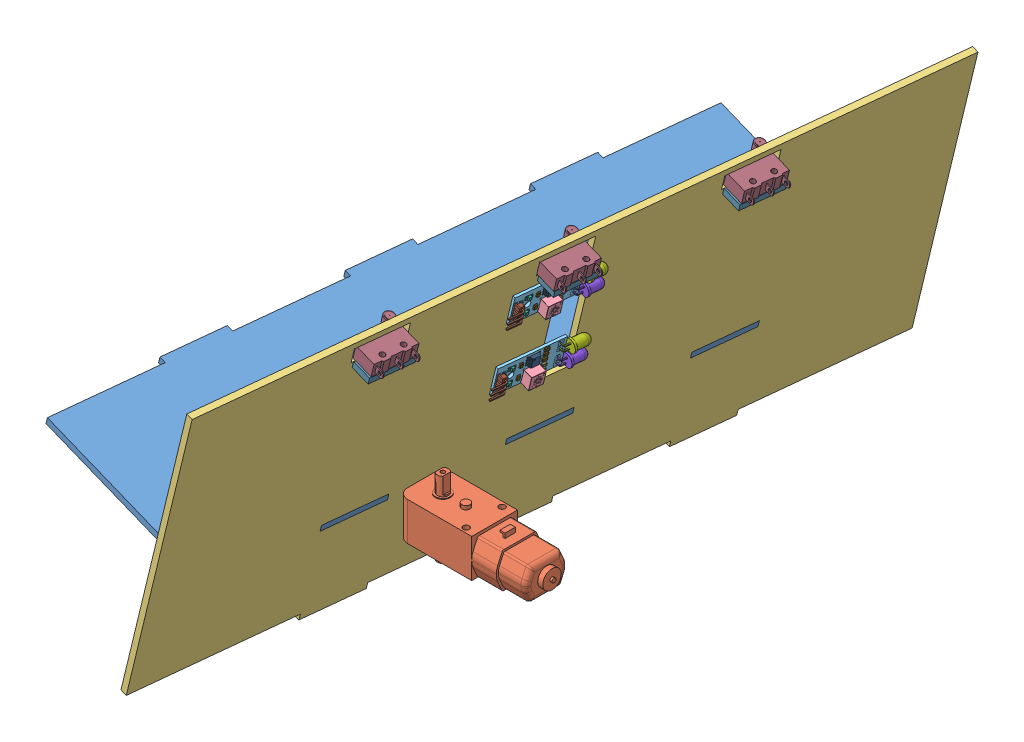
SolidWorks assembly Ensamblaje1, configuration Predeterminado. Lengths in mm.
Overall size (238.35 140.66 351.54).
45 component instances, 23 part files, 27 mates.
Components (placement in the parent):
- base-1: base [Predeterminado] at (-119.379 -243.9232 35.3077) x (0.963008 -0.251135 0.097703) z (-0.099836 0.004266 0.994995) size (91 3 300)
- Motor-1: Motor [Predeterminado] at (5.9789 -196.2669 168.1272) size (70.2 36.87 22.3)
- ParedDerecha-1: ParedDerecha [Predeterminado] at (-71.4428 -227.4941 40.047) x (0.099836 -0.004266 -0.994995) z (0.963008 -0.251135 0.097703) size (350 143 3)
- Sensor_IR.stp-1: Sensor_IR.stp [Predeterminado] at (-66.8981 -216.5746 54.0241) x (0.099836 -0.004266 -0.994995) z (0.963008 -0.251135 0.097703) size (45.22 14 7.87)
  - 3362P-1-102LF.stp-1: 3362P-1-102LF.stp [Predeterminado] at (0.5 -3.2 1.53) x (1 0 0) z (0 -1 0) size (6.6 7.58 6.6)
  - IR_Sensor_FC-51_1.stp-1: IR_Sensor_FC-51_1.stp [Predeterminado] at origin size (31 14 1.25)
  - KPTR-3216CGCK.stp-1: KPTR-3216CGCK.stp [Predeterminado] at (-8.7 3.8 1.45) x (1 0 0) z (0 0 -1) size (3.2 1.6 1.05)
  - KPTR-3216CGCK.stp-2: KPTR-3216CGCK.stp [Predeterminado] at (-8.7 -3.8 1.45) x (1 0 0) z (0 0 -1) size (3.2 1.6 1.05)
  - LED 5mm.stp-1: LED 5mm.stp [Predeterminado] at (15.74 3.64 3) x (0 1 0) z (1 0 0) size (5.5 6.7 11.78)
  - LED 5mm_foto.stp-1: LED 5mm_foto.stp [Predeterminado] at (15.74 -3.64 3) x (0 1 0) z (1 0 0) size (5.5 6.7 11.78)
  - RESC-0805.stp-1: RESC-0805.stp [Predeterminado] at (-4.525 -3.15 1.2) x (0 -1 0) z (0 0 1) size (2.1 1.35 0.6)
  - RESC-0805.stp-2: RESC-0805.stp [Predeterminado] at (-4.525 3.25 1.2) x (0 1 0) z (0 0 1) size (2.1 1.35 0.6)
  - SOIC8-150-50.stp-1: SOIC8-150-50.stp [Predeterminado] at (0.55 3.85 1.2) x (1 0 0) z (0 -1 0) size (6 1.91 4.9)
  - 1 Pin 2.54 mm Right Angle Single Row Pin Header Male 90 degrees Needle Connector.stp-1: 1 Pin 2.54 mm Right Angle Single Row Pin Header Male 90 degrees Needle Connector.stp [Predeterminado] at (-13.5 2.54 -1.76) x (-1 0 0) z (0 0 1) size (8.45 2.54 7.3)
  - 1 Pin 2.54 mm Right Angle Single Row Pin Header Male 90 degrees Needle Connector.stp-2: 1 Pin 2.54 mm Right Angle Single Row Pin Header Male 90 degrees Needle Connector.stp [Predeterminado] at (-13.5 0 -1.76) x (-1 0 0) z (0 0 1) size (8.45 2.54 7.3)
  - 1 Pin 2.54 mm Right Angle Single Row Pin Header Male 90 degrees Needle Connector.stp-3: 1 Pin 2.54 mm Right Angle Single Row Pin Header Male 90 degrees Needle Connector.stp [Predeterminado] at (-13.5 -2.54 -1.76) x (-1 0 0) z (0 0 1) size (8.45 2.54 7.3)
  - RESC-0805.stp-3: RESC-0805.stp [Predeterminado] at (6.45 5.625 1.2) size (2.1 1.35 0.6)
  - RESC-0805.stp-4: RESC-0805.stp [Predeterminado] at (6.45 3.085 1.2) size (2.1 1.35 0.6)
  - RESC-0805.stp-5: RESC-0805.stp [Predeterminado] at (6.45 0.545 1.2) size (2.1 1.35 0.6)
  - CAPC-0805-T0.95-BN.stp-1: CAPC-0805-T0.95-BN.stp [Predeterminado] at (6.45 -1.995 1.2) size (2.1 1.35 0.95)
  - CAPC-0805-T0.95-BN.stp-2: CAPC-0805-T0.95-BN.stp [Predeterminado] at (6.45 -4.535 1.2) size (2.1 1.35 0.95)
- Fin_Carrera.step-1: Fin_Carrera.step [Predeterminado] at (-50.8661 -171.0598 50.7642) x (-0.099836 0.004266 0.994995) z (-0.250295 -0.967943 -0.020964) size (22.47 22.8 6.34)
- Sensor_IR.stp-2: Sensor_IR.stp [Predeterminado] at (-57.8874 -181.7286 54.7788) x (0.099836 -0.004266 -0.994995) z (0.963008 -0.251135 0.097703) size (45.22 14 7.87)
  - 3362P-1-102LF.stp-1: 3362P-1-102LF.stp [Predeterminado] at (0.5 -3.2 1.53) x (1 0 0) z (0 -1 0) size (6.6 7.58 6.6)
  - IR_Sensor_FC-51_1.stp-1: IR_Sensor_FC-51_1.stp [Predeterminado] at origin size (31 14 1.25)
  - KPTR-3216CGCK.stp-1: KPTR-3216CGCK.stp [Predeterminado] at (-8.7 3.8 1.45) x (1 0 0) z (0 0 -1) size (3.2 1.6 1.05)
  - KPTR-3216CGCK.stp-2: KPTR-3216CGCK.stp [Predeterminado] at (-8.7 -3.8 1.45) x (1 0 0) z (0 0 -1) size (3.2 1.6 1.05)
  - LED 5mm.stp-1: LED 5mm.stp [Predeterminado] at (15.74 3.64 3) x (0 1 0) z (1 0 0) size (5.5 6.7 11.78)
  - LED 5mm_foto.stp-1: LED 5mm_foto.stp [Predeterminado] at (15.74 -3.64 3) x (0 1 0) z (1 0 0) size (5.5 6.7 11.78)
  - RESC-0805.stp-1: RESC-0805.stp [Predeterminado] at (-4.525 -3.15 1.2) x (0 -1 0) z (0 0 1) size (2.1 1.35 0.6)
  - RESC-0805.stp-2: RESC-0805.stp [Predeterminado] at (-4.525 3.25 1.2) x (0 1 0) z (0 0 1) size (2.1 1.35 0.6)
  - SOIC8-150-50.stp-1: SOIC8-150-50.stp [Predeterminado] at (0.55 3.85 1.2) x (1 0 0) z (0 -1 0) size (6 1.91 4.9)
  - 1 Pin 2.54 mm Right Angle Single Row Pin Header Male 90 degrees Needle Connector.stp-1: 1 Pin 2.54 mm Right Angle Single Row Pin Header Male 90 degrees Needle Connector.stp [Predeterminado] at (-13.5 2.54 -1.76) x (-1 0 0) z (0 0 1) size (8.45 2.54 7.3)
  - 1 Pin 2.54 mm Right Angle Single Row Pin Header Male 90 degrees Needle Connector.stp-2: 1 Pin 2.54 mm Right Angle Single Row Pin Header Male 90 degrees Needle Connector.stp [Predeterminado] at (-13.5 0 -1.76) x (-1 0 0) z (0 0 1) size (8.45 2.54 7.3)
  - 1 Pin 2.54 mm Right Angle Single Row Pin Header Male 90 degrees Needle Connector.stp-3: 1 Pin 2.54 mm Right Angle Single Row Pin Header Male 90 degrees Needle Connector.stp [Predeterminado] at (-13.5 -2.54 -1.76) x (-1 0 0) z (0 0 1) size (8.45 2.54 7.3)
  - RESC-0805.stp-3: RESC-0805.stp [Predeterminado] at (6.45 5.625 1.2) size (2.1 1.35 0.6)
  - RESC-0805.stp-4: RESC-0805.stp [Predeterminado] at (6.45 3.085 1.2) size (2.1 1.35 0.6)
  - RESC-0805.stp-5: RESC-0805.stp [Predeterminado] at (6.45 0.545 1.2) size (2.1 1.35 0.6)
  - CAPC-0805-T0.95-BN.stp-1: CAPC-0805-T0.95-BN.stp [Predeterminado] at (6.45 -1.995 1.2) size (2.1 1.35 0.95)
  - CAPC-0805-T0.95-BN.stp-2: CAPC-0805-T0.95-BN.stp [Predeterminado] at (6.45 -4.535 1.2) size (2.1 1.35 0.95)
- soporteFinCarrera-1: soporteFinCarrera [Predeterminado] at (-58.4739 -172.2659 54.1769) x (0.099836 -0.004266 -0.994995) z (0.963008 -0.251135 0.097703) size (21 3 12)
- soporteFinCarrera-2: soporteFinCarrera [Predeterminado] at (-48.4882 -169.7567 -37.7972) x (-0.099836 0.004266 0.994995) z (0.963008 -0.251135 0.097703) size (21 3 12)
- soporteFinCarrera-3: soporteFinCarrera [Predeterminado] at (-64.9611 -169.0527 126.3769) x (-0.099836 0.004266 0.994995) z (0.963008 -0.251135 0.097703) size (21 3 12)
- Fin_Carrera.step-2: Fin_Carrera.step [Predeterminado] at (-42.5099 -171.4169 -32.5169) x (-0.099836 0.004266 0.994995) z (-0.250295 -0.967943 -0.020964) size (22.47 22.8 6.34)
- Fin_Carrera.step-3: Fin_Carrera.step [Predeterminado] at (-58.9828 -170.713 131.6573) x (-0.099836 0.004266 0.994995) z (-0.250295 -0.967943 -0.020964) size (22.47 22.8 6.34)
Mates (geometry in assembly coordinates):
- Coincidente1: coincident anti-aligned: plane of base-1 through (-119.379 -243.9232 35.3077) normal (-0.250295 -0.967943 -0.020964); plane of ParedDerecha-1 through (-75.5621 -255.3499 39.7531) normal (0.250295 0.967943 0.020964)
- Coincidente2: coincident anti-aligned: plane of base-1 through (-84.4391 -251.4046 106.6851) normal (0.099836 -0.004266 -0.994995); plane of ParedDerecha-1 through (-75.2927 -227.9595 107.5023) normal (-0.099836 0.004266 0.994995)
- Coincidente3: coincident aligned: plane of base-1 through (-84.5452 -252.0301 136.828) normal (0.963008 -0.251135 0.097703); plane of ParedDerecha-1 through (-68.5538 -228.2475 40.3401) normal (0.963008 -0.251135 0.097703)
- Coincidente4: coincident anti-aligned: plane of ParedDerecha-1 through (-68.5538 -228.2475 40.3401) normal (0.963008 -0.251135 0.097703); plane of Sensor_IR.stp-1/IR_Sensor_FC-51_1.stp-1 through (-66.8981 -216.5746 54.0241) normal (-0.963008 0.251135 -0.097703)
- Concéntrica1: concentric anti-aligned: cylinder of ParedDerecha-1 through (-67.7467 -216.5383 62.4816) axis (-0.963008 0.251135 -0.097703) radius 1.5; cylinder of Sensor_IR.stp-1/IR_Sensor_FC-51_1.stp-1 through (-67.7467 -216.5383 62.4816) axis (0.963008 -0.251135 0.097703) radius 1.5
- Paralelo1: parallel aligned: plane of ParedDerecha-1 through (-51.0332 -160.4915 41.8076) normal (0.250295 0.967943 0.020964); plane of Sensor_IR.stp-1/IR_Sensor_FC-51_1.stp-1 through (-63.5985 -209.8651 38.7484) normal (0.250295 0.967943 0.020964)
- Coincidente6: coincident anti-aligned: plane of ParedDerecha-1 through (-68.5538 -228.2475 40.3401) normal (0.963008 -0.251135 0.097703); plane of Sensor_IR.stp-2/IR_Sensor_FC-51_1.stp-1 through (-57.8874 -181.7286 54.7788) normal (-0.963008 0.251135 -0.097703)
- Concéntrica2: concentric anti-aligned: cylinder of ParedDerecha-1 through (-58.736 -181.6924 63.2363) axis (-0.963008 0.251135 -0.097703) radius 1.5; cylinder of Sensor_IR.stp-2/IR_Sensor_FC-51_1.stp-1 through (-58.736 -181.6924 63.2363) axis (0.963008 -0.251135 0.097703) radius 1.5
- Paralelo2: parallel aligned: plane of ParedDerecha-1 through (-51.0332 -160.4915 41.8076) normal (0.250295 0.967943 0.020964); plane of Sensor_IR.stp-2/IR_Sensor_FC-51_1.stp-1 through (-54.5879 -175.0192 39.5031) normal (0.250295 0.967943 0.020964)
- Coincidente8: coincident anti-aligned: plane of ParedDerecha-1 through (-54.287 -173.0747 41.5351) normal (0.250295 0.967943 0.020964); plane of soporteFinCarrera-1 through (-58.4739 -172.2659 54.1769) normal (-0.250295 -0.967943 -0.020964)
- Coincidente9: coincident anti-aligned: plane of ParedDerecha-1 through (-69.8517 -228.192 53.2751) normal (0.099836 -0.004266 -0.994995); plane of soporteFinCarrera-1 through (-54.834 -170.1155 54.5329) normal (-0.099836 0.004266 0.994995)
- Coincidente10: coincident anti-aligned: plane of ParedDerecha-1 through (-68.5538 -228.2475 40.3401) normal (0.963008 -0.251135 0.097703); plane of soporteFinCarrera-1 through (-53.8356 -170.1581 44.5829) normal (-0.963008 0.251135 -0.097703)
- Coincidente11: coincident anti-aligned: plane of Fin_Carrera.step-1 through (-50.5724 -171.1364 50.794) normal (-0.250295 -0.967943 -0.020964); plane of soporteFinCarrera-1 through (-57.723 -169.362 54.2398) normal (0.250295 0.967943 0.020964)
- Concéntrica3: concentric anti-aligned: cylinder of Fin_Carrera.step-1 through (-47.6609 -171.7869 46.0637) axis (0.250295 0.967943 0.020964) radius 1.25; cylinder of soporteFinCarrera-1 through (-47.6609 -171.7869 46.0637) axis (-0.250295 -0.967943 -0.020964) radius 1.175
- Concéntrica4: concentric anti-aligned: cylinder of Fin_Carrera.step-1 through (-48.6094 -171.7463 55.5162) axis (0.250295 0.967943 0.020964) radius 1.25; cylinder of soporteFinCarrera-1 through (-48.6094 -171.7463 55.5162) axis (-0.250295 -0.967943 -0.020964) radius 1.175
- Coincidente13: coincident anti-aligned: plane of ParedDerecha-1 through (-54.287 -173.0747 41.5351) normal (0.250295 0.967943 0.020964); plane of soporteFinCarrera-3 through (-65.712 -171.9566 126.314) normal (-0.250295 -0.967943 -0.020964)
- Coincidente15: coincident anti-aligned: plane of ParedDerecha-1 through (-78.0881 -227.84 135.3621) normal (0.099836 -0.004266 -0.994995); plane of soporteFinCarrera-3 through (-66.7103 -171.9139 136.264) normal (-0.099836 0.004266 0.994995)
- Coincidente16: coincident aligned: plane of ParedDerecha-1 through (-71.4428 -227.4941 40.047) normal (-0.963008 0.251135 -0.097703); plane of soporteFinCarrera-3 through (-65.712 -171.9566 126.314) normal (-0.963008 0.251135 -0.097703)
- Coincidente18: coincident anti-aligned: plane of soporteFinCarrera-3 through (-64.9611 -169.0527 126.3769) normal (0.250295 0.967943 0.020964); plane of Fin_Carrera.step-3 through (-58.6891 -170.7896 131.6871) normal (-0.250295 -0.967943 -0.020964)
- Concéntrica5: concentric aligned: cylinder of soporteFinCarrera-3 through (-57.4769 -174.3033 136.3464) axis (0.250295 0.967943 0.020964) radius 1.175; cylinder of Fin_Carrera.step-3 through (-56.726 -171.3995 136.4093) axis (0.250295 0.967943 0.020964) radius 1.25
- Concéntrica6: concentric aligned: cylinder of soporteFinCarrera-3 through (-56.5284 -174.3438 126.8939) axis (0.250295 0.967943 0.020964) radius 1.175; cylinder of Fin_Carrera.step-3 through (-55.7776 -171.44 126.9568) axis (0.250295 0.967943 0.020964) radius 1.25
- Coincidente20: coincident anti-aligned: plane of ParedDerecha-1 through (-54.287 -173.0747 41.5351) normal (0.250295 0.967943 0.020964); plane of soporteFinCarrera-2 through (-49.2391 -172.6605 -37.8601) normal (-0.250295 -0.967943 -0.020964)
- Coincidente21: coincident anti-aligned: plane of ParedDerecha-1 through (-61.6152 -228.544 -28.812) normal (0.099836 -0.004266 -0.994995); plane of soporteFinCarrera-2 through (-50.2374 -172.6178 -27.9102) normal (-0.099836 0.004266 0.994995)
- Coincidente22: coincident aligned: plane of ParedDerecha-1 through (-71.4428 -227.4941 40.047) normal (-0.963008 0.251135 -0.097703); plane of soporteFinCarrera-2 through (-49.2391 -172.6605 -37.8601) normal (-0.963008 0.251135 -0.097703)
- Coincidente23: coincident anti-aligned: plane of soporteFinCarrera-2 through (-48.4882 -169.7567 -37.7972) normal (0.250295 0.967943 0.020964); plane of Fin_Carrera.step-2 through (-42.2162 -171.4935 -32.4871) normal (-0.250295 -0.967943 -0.020964)
- Concéntrica9: concentric aligned: cylinder of soporteFinCarrera-2 through (-40.0556 -175.0478 -37.2802) axis (0.250295 0.967943 0.020964) radius 1.175; cylinder of Fin_Carrera.step-2 through (-39.3047 -172.144 -37.2173) axis (0.250295 0.967943 0.020964) radius 1.25
- Concéntrica10: concentric aligned: cylinder of soporteFinCarrera-2 through (-41.004 -175.0073 -27.8278) axis (0.250295 0.967943 0.020964) radius 1.175; cylinder of Fin_Carrera.step-2 through (-40.2531 -172.1034 -27.7649) axis (0.250295 0.967943 0.020964) radius 1.25
